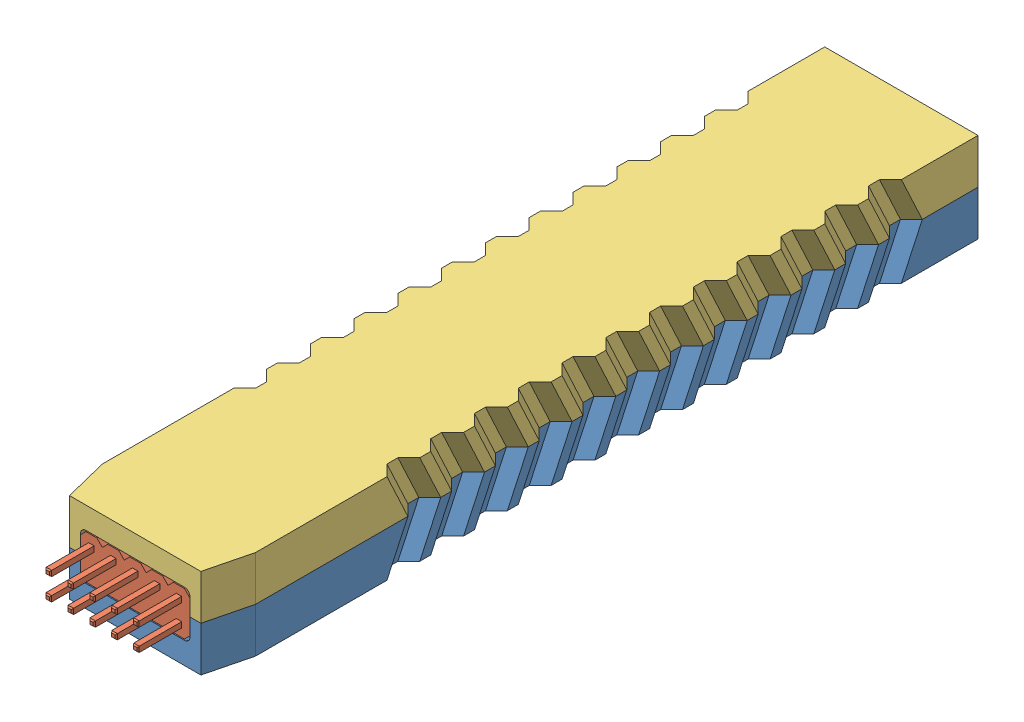
SolidWorks assembly DeviceConnectorCable, configuration Device Connector. Lengths in mm.
Overall size (14.04 8.52 74.5).
4 component instances, 4 part files, 24 mates.
Components (placement in the parent):
- DeviceEnclosureLid^DeviceConnectorCable-1: DeviceEnclosureLid^DeviceConnectorCable [Device Enclosure Lid] at (0 -4.1 -35) x (0 0 -1) z (1 0 0) size (70.11 6.22 14.04) (virtual)
- PLD2-NN (DS-1025-05 - 2xNN) 2mm^DeviceConnectorCable-1: PLD2-NN (DS-1025-05 - 2xNN) 2mm^DeviceConnectorCable [Connector DS1021-2x5] at (4 0 0) x (-1 0 0) z (0 0 -1) size (10 4 8.8) (virtual)
- DeviceEnclosureBody^DeviceConnectorCable-1: DeviceEnclosureBody^DeviceConnectorCable [Device Enclosure Body] at (0 4.1 -35) x (0 0 -1) z (-1 0 0) size (70.5 6.52 14.04) (virtual)
- RoundCable^DeviceConnectorCable-1: RoundCable^DeviceConnectorCable [Default] at (0.001 0 -21.5457) x (0 0 -1) z (-1 0 0) size (48.31 3 8.21) (virtual)
Mates (geometry in assembly coordinates):
- Coincident4: coincident aligned: plane of DeviceEnclosureLid^DeviceConnectorCable-1 through (0 -2.1 0) normal (0 0 1); plane of Lid^cable-1 through (0 2.1 0.013) normal (0 0 1)
- Coincident5: coincident anti-aligned: plane of DeviceEnclosureLid^DeviceConnectorCable-1 through (0 0 -35) normal (0 1 0); plane of Lid^cable-1 through (0 0.1 -27.487) normal (0 -1 0)
- Concentric1: concentric anti-aligned: cylinder of Self Tapping Cross recessed Screw 4Plastic^cable-1 through (-14 -8 -8.287) axis (0 -1 0) radius 0.78; cylinder of Lid^cable-1 through (-14 2.1 -8.287) axis (0 1 0) radius 1.5
- Coincident7: coincident aligned: cone of Self Tapping Cross recessed Screw 4Plastic^cable-1 through (-14 0.48 -8.287) axis (0 -1 0); cone of Lid^cable-1 through (-14 2.1 -8.287) axis (0 -1 0)
- Concentric2: concentric anti-aligned: cylinder of Self Tapping Cross recessed Screw 4Plastic^cable-2 through (14 -8 -8.287) axis (0 -1 0) radius 0.78; cylinder of Lid^cable-1 through (14 2.1 -8.287) axis (0 1 0) radius 1.5
- Coincident8: coincident aligned: cone of Self Tapping Cross recessed Screw 4Plastic^cable-2 through (14 0.48 -8.287) axis (0 -1 0); cone of Lid^cable-1 through (14 2.1 -8.287) axis (0 -1 0)
- Coincident10: coincident aligned: plane of board^cable-1 through (-0.9944 1 -14.4999) normal (0 1 0); plane of RibbonCable^DeviceConnector-1 through (0 0 -17.6612) normal (0 1 0)
- Coincident11: coincident anti-aligned: plane of board^cable-1 through (-0.9944 1 -14.4999) normal (0 1 0); plane of PBD-20-1 through (10.4356 1 0.5001) normal (0 -1 0)
- Coincident12: coincident anti-aligned: plane of board^cable-1 through (-13.8944 1.75 0.5001) normal (0 0 1); plane of PBD-20-1 through (9.1656 -1.54 0.5001) normal (0 0 -1)
- Coincident13: coincident anti-aligned: plane of DeviceEnclosureLid^DeviceConnectorCable-1 through (0 -4.1 -35) normal (1 0 0); plane of PBD-20-1 through (-0.9944 -0.27 0.5001) normal (-1 0 0)
- Coincident14: coincident anti-aligned: plane of RibbonCable^DeviceConnector-1 through (0 0 -17.6612) normal (1 0 0); plane of PBD-20-1 through (-0.9944 -0.27 0.5001) normal (-1 0 0)
- Coincident15: coincident anti-aligned: plane of DeviceEnclosureLid^DeviceConnectorCable-1 through (0 -1.05 -35) normal (0 1 0); plane of PBD-20-1 through (10.4356 1 0.5001) normal (0 -1 0)
- Coincident16: coincident aligned: plane of board^cable-1 through (-0.9944 1 -14.4999) normal (-1 0 0); plane of PBD-20-1 through (-0.9944 -0.27 0.5001) normal (-1 0 0)
- Concentric3: concentric anti-aligned: cylinder of board^cable-1 through (13.0056 0.25 -6.9999) axis (0 1 0) radius 3.4; cylinder of EnclosureBody^cable-1 through (5.0056 3.65 -8.287) axis (0 -1 0) radius 3.1
- Coincident17: coincident aligned: plane of DeviceEnclosureLid^DeviceConnectorCable-1 through (0 -4.1 -35) normal (1 0 0); plane of Lid^cable-1 through (0 0.1 -27.487) normal (1 0 0)
- Coincident18: coincident anti-aligned: plane of board^cable-1 through (-13.8944 1.75 0.5001) normal (0 0 1); plane of PLD2-NN (DS-1025-05 - 2xNN) 2mm^DeviceConnector-1 through (10 1.3335 -1.6) normal (0 0 -1)
- Coincident23: coincident anti-aligned: plane of DeviceEnclosureLid^DeviceConnectorCable-1 through (-5 0 -35) normal (1 0 0); plane of PLD2-NN (DS-1025-05 - 2xNN) 2mm^DeviceConnector-1 through (-5 2 -2) normal (-1 0 0)
- Coincident24: coincident anti-aligned: plane of DeviceEnclosureLid^DeviceConnectorCable-1 through (0 0 -35) normal (0 1 0); plane of DeviceEnclosureBody^DeviceConnectorCable-1 through (0 0 -35) normal (0 -1 0)
- Coincident25: coincident aligned: plane of RibbonCable^DeviceConnector-1 through (0 0 -17.6612) normal (1 0 0); plane of PLD2-NN (DS-1025-05 - 2xNN) 2mm^DeviceConnector-1 through (0 0 0) normal (1 0 0)
- Coincident26: coincident anti-aligned: plane of PLD2-NN (DS-1025-05 - 2xNN) 2mm^DeviceConnector-1 through (4 0 -2) normal (0 0 -1); plane of DeviceEnclosureBody^DeviceConnectorCable-1 through (3.5 0.1 -2) normal (0 0 1)
- Coincident28: coincident aligned: plane of RibbonCable^DeviceConnector-1 through (0 0 -17.6612) normal (0 1 0); plane of PLD2-NN (DS-1025-05 - 2xNN) 2mm^DeviceConnector-1 through (4 0 0) normal (0 1 0)
- Coincident29: coincident aligned: plane of DeviceEnclosureLid^DeviceConnectorCable-1 through (0 -2.1 0) normal (0 0 1); plane of DeviceEnclosureBody^DeviceConnectorCable-1 through (0 2.1 0) normal (0 0 1)
- Coincident30: coincident anti-aligned: plane of PLD2-NN (DS-1025-05 - 2xNN) 2mm^DeviceConnector-1 through (4 0 0) normal (0 1 0); plane of DeviceEnclosureBody^DeviceConnectorCable-1 through (0 0 -35) normal (0 -1 0)
- Coincident31: coincident anti-aligned: plane of PLD2-NN (DS-1025-05 - 2xNN) 2mm^DeviceConnector-1 through (0 0 0) normal (1 0 0); plane of DeviceEnclosureBody^DeviceConnectorCable-1 through (0 4.1 -35) normal (-1 0 0)
